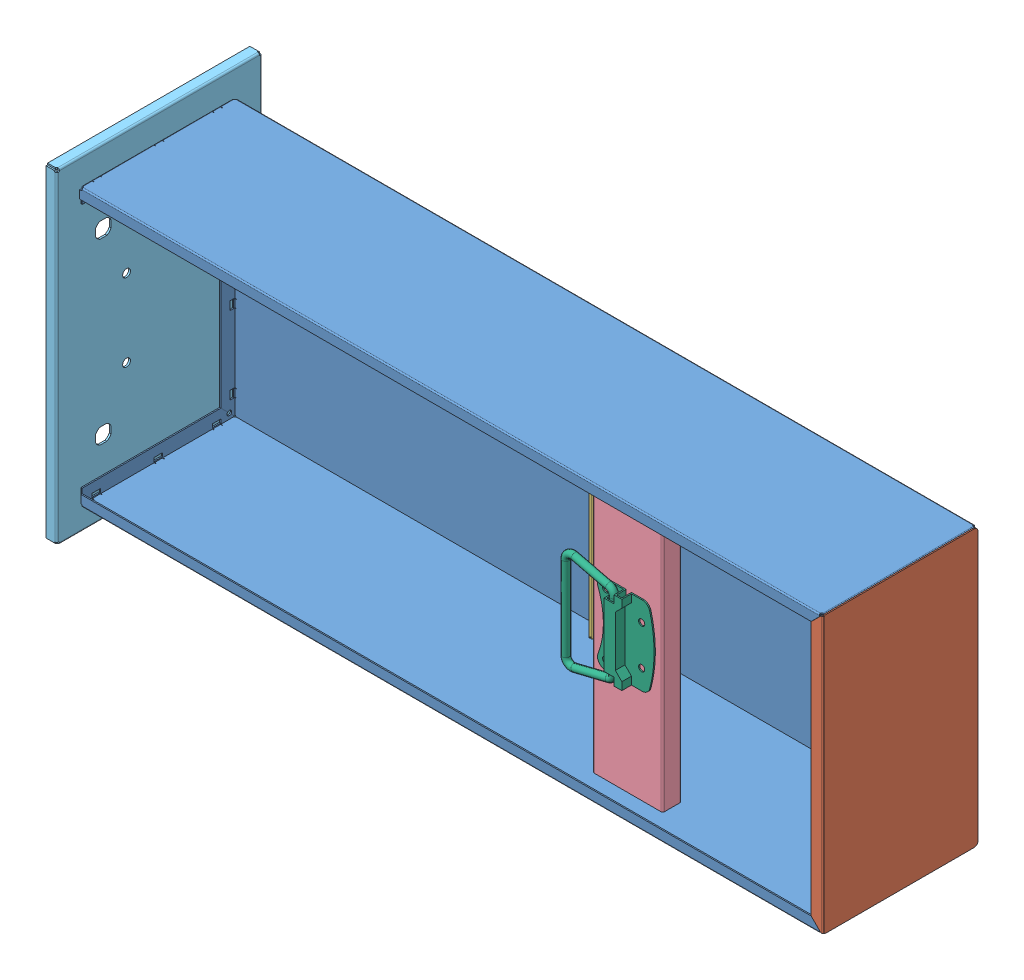
SolidWorks assembly 抽屜, configuration 預設. Lengths in mm.
Overall size (972.76 419.92 264.92).
6 component instances, 6 part files, 16 mates.
Components (placement in the parent):
- LB-A54-09-2-1: LB-A54-09-2 [預設] at (-512.4212 -368.1131 -100.0963) size (957.21 356.22 200.21)
- LB-A54-09-3-2: LB-A54-09-3 [預設] at (462.7788 195.2869 -99.9963) x (0 -1 0) z (-1 0 0) size (356 200.1 15.3)
- LB-A54-09-4-1: LB-A54-09-4 [預設] at (-33.7594 -159.1131 -61.2317) x (0 1 0) z (-0.707107 0 -0.707107) size (352 26.8 26.8)
- LB-A54-09-5-1: LB-A54-09-5 [預設] at (3206.1948 -8749.2988 66.2037) x (0 1 0) z (0 0 1) size (356 90.59 24.59)
- LB-A54-09-1-2: LB-A54-09-1 [預設] at (-498.3212 -201.0531 -145.4363) x (0 1 0) z (1 0 0) size (419.92 264.92 13.96)
- 箱丸把手 ET-10102-1: 箱丸把手 ET-10102 [預設] at (142.0057 66.8869 68.5037) x (0 -1 0) z (0 0 1) size (134.47 112.5 14)
Mates (geometry in assembly coordinates):
- 重合/共線/共點3: coincident anti-aligned: plane of LB-A54-09-2-1 through (461.1788 -1113.1131 -451.4963) normal (1 0 0); plane of LB-A54-09-3-2 through (461.1788 195.2869 98.5037) normal (-1 0 0)
- 重合/共線/共點4: coincident aligned: plane of LB-A54-09-2-1 through (-494.4212 -709.1131 100.1037) normal (0 0 1); plane of LB-A54-09-3-2 through (461.1788 195.2869 100.1037) normal (0 0 1)
- 重合/共線/共點6: coincident: point of LB-A54-09-2-1; plane of LB-A54-09-3-2 through (460.4717 -160.006 98.5037) normal (-0.707107 -0.707107 0)
- 重合/共線/共點7: coincident: plane of LB-A54-09-2-1 through (-494.4212 193.8869 -98.4963) normal (0 0 1); line of LB-A54-09-4-1 through (-34.3958 -154.1131 -98.4963) axis (0 1 0)
- 重合/共線/共點8: coincident: plane of LB-A54-09-2-1 through (-494.4212 193.8869 -98.4963) normal (0 0 1); line of LB-A54-09-4-1 through (0.2524 187.8869 -98.4963) axis (0 -1 0)
- 重合/共線/共點10: coincident anti-aligned: plane of LB-A54-09-2-1 through (-494.4212 -159.1131 -451.4963) normal (0 1 0); plane of LB-A54-09-4-1 through (-16.7535 -159.1131 -80.854) normal (0 -1 0)
- 平行相距2: distance = 457.7 mm: line of LB-A54-09-4-1 through (1.8788 187.8869 -96.8699) axis (0 -1 0); plane of LB-A54-09-2-1 through (459.5788 193.8869 -1052.4963) normal (-1 0 0)
- 重合/共線/共點12: coincident anti-aligned: plane of LB-A54-09-2-1 through (-494.4212 193.8869 -98.4963) normal (0 -1 0); plane of LB-A54-09-5-1 through (224.5788 193.8869 65.7077) normal (0 1 0)
- 平行相距3: distance = 30 mm anti-aligned: plane of LB-A54-09-5-1 through (159.2828 193.8869 68.5037) normal (0 0 1); plane of LB-A54-09-2-1 through (-494.4212 390.8869 98.5037) normal (0 0 -1)
- 重合/共線/共點15: coincident: plane of LB-A54-09-2-1 through (-496.0212 193.8869 -98.4963) normal (-1 0 0); plane of LB-A54-09-1-2 through (-496.0212 -189.0531 -133.4363) normal (1 0 0)
- 平行相距4: distance = 28 mm: plane of LB-A54-09-2-1 through (-494.4212 -160.7131 -451.4963) normal (0 -1 0); line of LB-A54-09-1-2 through (-496.0212 -188.7131 -131.9753) axis (0 0 1)
- 重合/共線/共點18: coincident anti-aligned: plane of LB-A54-09-5-1 through (159.2828 193.8869 68.5037) normal (0 0 1); plane of 箱丸把手 ET-10102-1 through (80.8017 15.8869 68.5037) normal (0 0 -1)
- 平行相距6: distance = 235 mm anti-aligned: plane of LB-A54-09-5-1 through (224.5788 193.8869 129.2077) normal (1 0 0); plane of LB-A54-09-2-1 through (459.5788 1147.8869 -98.4963) normal (-1 0 0)
- 平行相距7: distance = 127 mm anti-aligned: plane of LB-A54-09-2-1 through (-494.4212 193.8869 -98.4963) normal (0 -1 0); plane of 箱丸把手 ET-10102-1 through (80.8017 66.8869 70.1037) normal (0 1 0)
- 平行相距10: distance = 26.5468 mm: plane of 箱丸把手 ET-10102-1 through (162.8346 15.8869 82.5037) normal (-1 0 0); line of LB-A54-09-5-1 through (136.2878 -160.1131 68.5037) axis (0 1 0)
- 平行相距11: distance = 33 mm: plane of LB-A54-09-2-1 through (-494.4212 193.8869 -100.0963) normal (0 0 -1); line of LB-A54-09-1-2 through (-496.0212 225.486 -133.0963) axis (0 -1 0)
